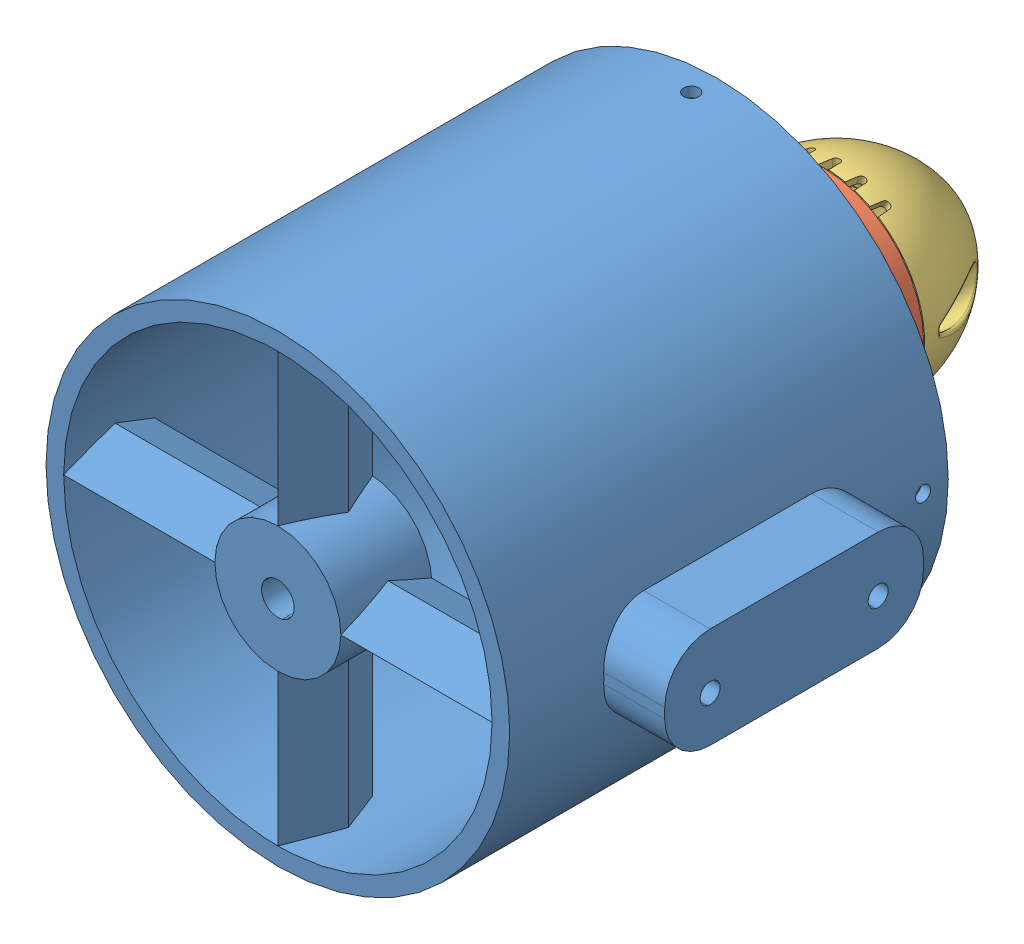
SolidWorks assembly montaj, configuration Varsayılan. Lengths in mm.
Overall size (107.02 95.04 133.69).
4 component instances, 4 part files, 6 mates.
Components (placement in the parent):
- arka parça-1: arka parça [Varsayılan] at (-20.7701 13.4447 115.5) size (104.09 92 87)
- tutucu-1: tutucu [Default] at (-22.8633 10.9473 69.3717) x (-1 0 0) z (0 0 -1) size (87.46 87.46 34.2)
- kafa-1: kafa [Default] at (-22.8633 10.9473 69.2145) x (1 0 0) z (0 0 -1) size (41.42 39.96 25.4)
- kanat-1: kanat [Default] at (-22.8633 10.9473 86.1193) x (-0.977363 -0.211571 0) z (0 0 -1) size (71.04 76.84 30.02)
Mates (geometry in assembly coordinates):
- Eş Merkezli1: concentric aligned: cylinder of tutucu-1 through (-38.7383 10.9473 48.6854) axis (0 0 -1) radius 2.35; circle of kafa-1
- Eş Merkezli2: concentric aligned: cylinder of tutucu-1 through (-6.9883 10.9473 48.6854) axis (0 0 -1) radius 2.35; circle of kafa-1
- Eş Merkezli3: concentric anti-aligned: cylinder of tutucu-1 through (-22.8633 10.9473 27.7697) axis (0 0 1) radius 5; cylinder of kanat-1 through (-22.8633 10.9473 107.2853) axis (0 0 -1) radius 3
- Eş Merkezli4: concentric anti-aligned: cylinder of arka parça-1 through (-22.8633 73.4447 53.5) axis (0 -1 0) radius 1.5; cylinder of tutucu-1 through (-22.8633 54.635 53.5) axis (0 1 0) radius 1.25
- Eş Merkezli5: concentric aligned: cylinder of arka parça-1 through (-22.8633 73.4447 53.5) axis (0 -1 0) radius 1.5; cylinder of tutucu-1 through (-22.8633 -32.7405 53.5) axis (0 -1 0) radius 1.25
- Eş Merkezli7: concentric anti-aligned: cylinder of arka parça-1 through (37.2299 10.9473 53.5) axis (-1 0 0) radius 1.5; cylinder of tutucu-1 through (20.8244 10.9473 53.5) axis (1 0 0) radius 1.25
